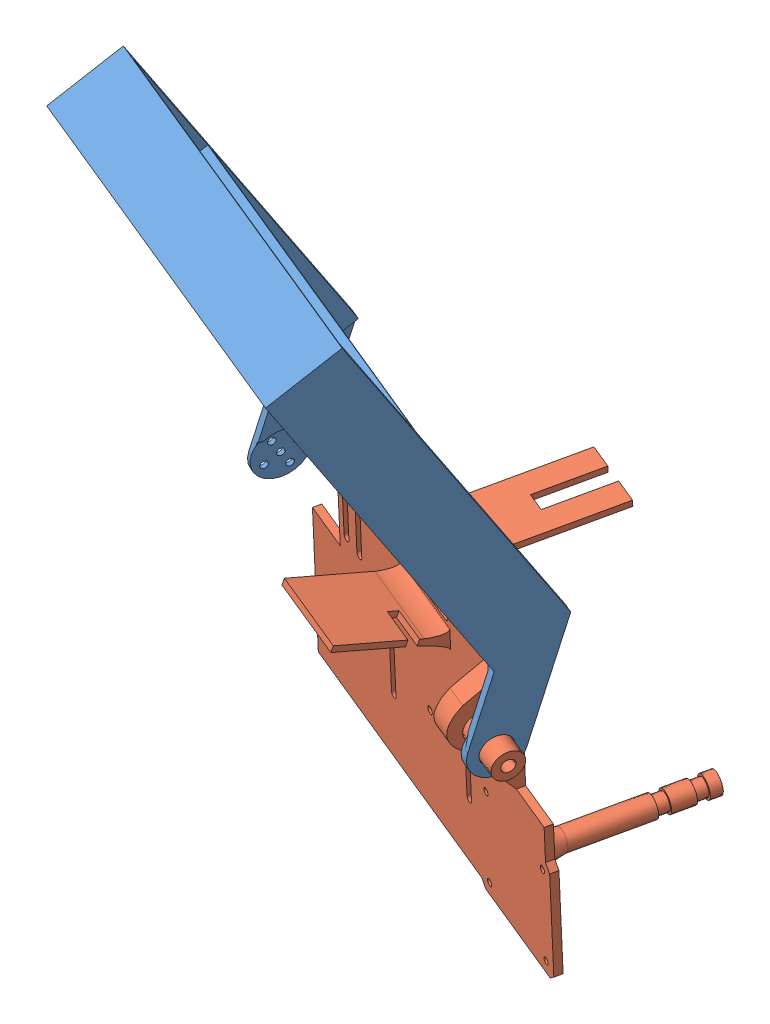
SolidWorks assembly 装配体1, configuration Default. Lengths in mm.
Overall size (246.56 384.14 296.94).
2 component instances, 2 part files, 1 mates.
Components (placement in the parent):
- BigBlue_V1.0(arm)-1: BigBlue_V1.0(arm) [默认] at (414.4706 8.0694 18.7496) x (0.941739 -0.128454 0.310848) z (0.063425 -0.839796 -0.539185) size (190 140 237.94)
- BigBlue_V1.0(deck)-1: BigBlue_V1.0(deck) [默认] at (362.833 -147.0996 89.7007) x (0.941739 -0.128454 0.310848) z (-0.323781 -0.095999 0.941249) size (190 140 119.38)
Mates (geometry in assembly coordinates):
- 同心2: concentric anti-aligned: cylinder of BigBlue_V1.0(arm)-1 through (532.0739 -61.4704 174.1812) axis (0.941739 -0.128454 0.310848) radius 7; cylinder of BigBlue_V1.0(deck)-1 through (542.2051 -62.8523 177.5253) axis (-0.941739 0.128454 -0.310848) radius 6.75
